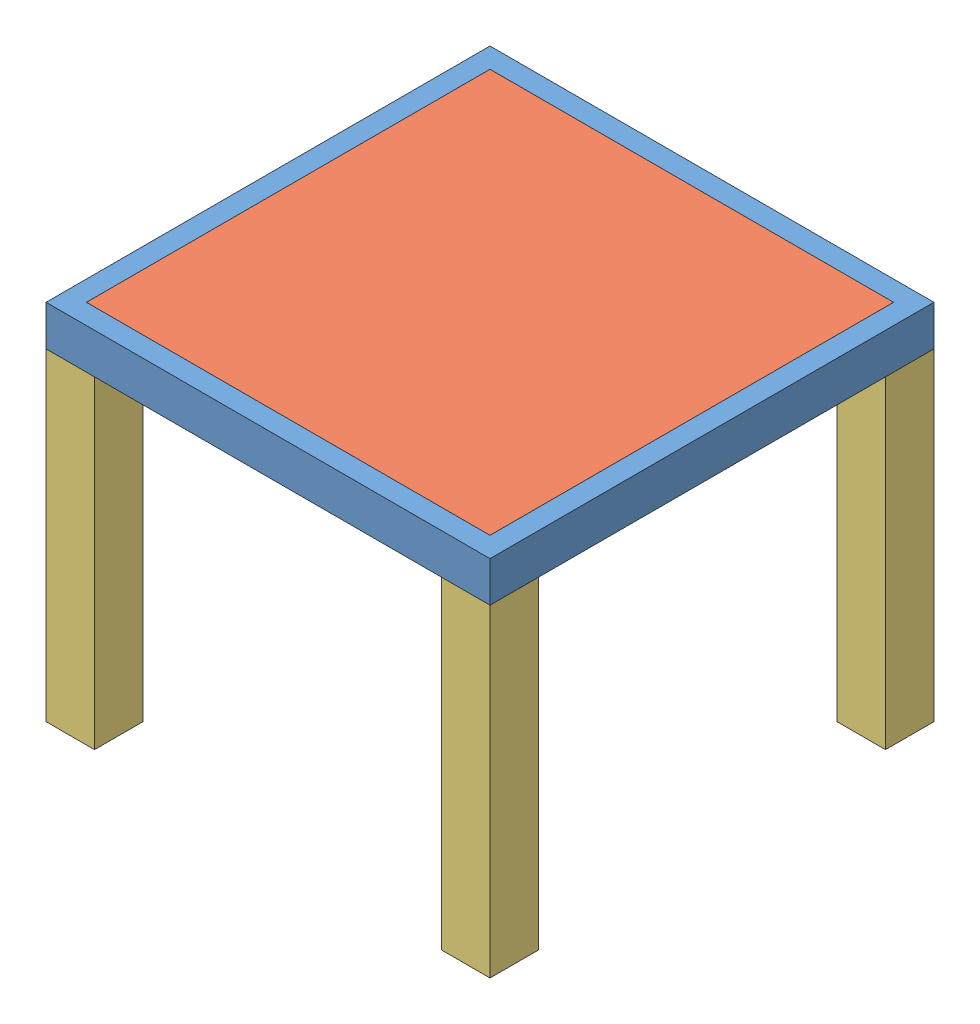
SolidWorks assembly groovegrid_lack, configuration Standard. Lengths in mm.
Overall size (550 450 550).
20 component instances, 4 part files, 9 mates.
Components (placement in the parent):
- groovegrid_lack_table-1: groovegrid_lack_table [Standard] at origin size (550 50 550)
- groovegrid_lack_glass-1: groovegrid_lack_glass [Standard] at (0 44 0) size (500 6 500)
- groovegrid_lack_foot-1: groovegrid_lack_foot [Standard] at (-245 -400 -245) size (60 400 60)
- groovegrid_lack_foot-2: groovegrid_lack_foot [Standard] at (-245 -400 245) size (60 400 60)
- groovegrid_lack_foot-3: groovegrid_lack_foot [Standard] at (245 -400 245) size (60 400 60)
- groovegrid_lack_foot-4: groovegrid_lack_foot [Standard] at (245 -400 -245) size (60 400 60)
- groovegrid_lack_led-1: groovegrid_lack_led [Standard] at (16.5 10 214.5) size (462 2.2 10)
- groovegrid_lack_led-2: groovegrid_lack_led [Standard] at (16.5 10 181.5) size (462 2.2 10)
- groovegrid_lack_led-3: groovegrid_lack_led [Standard] at (16.5 10 148.5) size (462 2.2 10)
- groovegrid_lack_led-4: groovegrid_lack_led [Standard] at (16.5 10 115.5) size (462 2.2 10)
- groovegrid_lack_led-5: groovegrid_lack_led [Standard] at (16.5 10 82.5) size (462 2.2 10)
- groovegrid_lack_led-6: groovegrid_lack_led [Standard] at (16.5 10 49.5) size (462 2.2 10)
- groovegrid_lack_led-7: groovegrid_lack_led [Standard] at (16.5 10 16.5) size (462 2.2 10)
- groovegrid_lack_led-8: groovegrid_lack_led [Standard] at (16.5 10 -16.5) size (462 2.2 10)
- groovegrid_lack_led-9: groovegrid_lack_led [Standard] at (16.5 10 -49.5) size (462 2.2 10)
- groovegrid_lack_led-10: groovegrid_lack_led [Standard] at (16.5 10 -82.5) size (462 2.2 10)
- groovegrid_lack_led-11: groovegrid_lack_led [Standard] at (16.5 10 -115.5) size (462 2.2 10)
- groovegrid_lack_led-12: groovegrid_lack_led [Standard] at (16.5 10 -148.5) size (462 2.2 10)
- groovegrid_lack_led-13: groovegrid_lack_led [Standard] at (16.5 10 -181.5) size (462 2.2 10)
- groovegrid_lack_led-14: groovegrid_lack_led [Standard] at (16.5 10 -214.5) size (462 2.2 10)
Mates (geometry in assembly coordinates):
- Coincident1: coincident: point of groovegrid_lack_table-1; point of groovegrid_lack_glass-1
- Coincident2: coincident: point of groovegrid_lack_table-1; point of groovegrid_lack_foot-1
- Coincident3: coincident: point of groovegrid_lack_table-1; point of groovegrid_lack_foot-2
- Coincident4: coincident: point of groovegrid_lack_table-1; point of groovegrid_lack_foot-3
- Coincident5: coincident: point of groovegrid_lack_table-1; point of groovegrid_lack_foot-4
- Coincident7: coincident: moEndPointRef_w of groovegrid_lack_led-1; plane of assembly
- Parallel1: parallel: line of groovegrid_lack_led-1 through (-231 11 219.5) axis (1 0 0); line of groovegrid_lack_table-1 through (-220.8656 10 250) axis (1 0 0)
- Coincident9: coincident: plane of groovegrid_lack_table-1 through (0 10 0) normal (0 1 0); plane of groovegrid_lack_led-1 through (16.5 10 214.5) normal (0 -1 0)
- Distance2: distance = 30.5 mm: line of groovegrid_lack_table-1 through (-220.8656 10 250) axis (1 0 0); line of groovegrid_lack_led-1 through (-231 10 219.5) axis (1 0 0)
